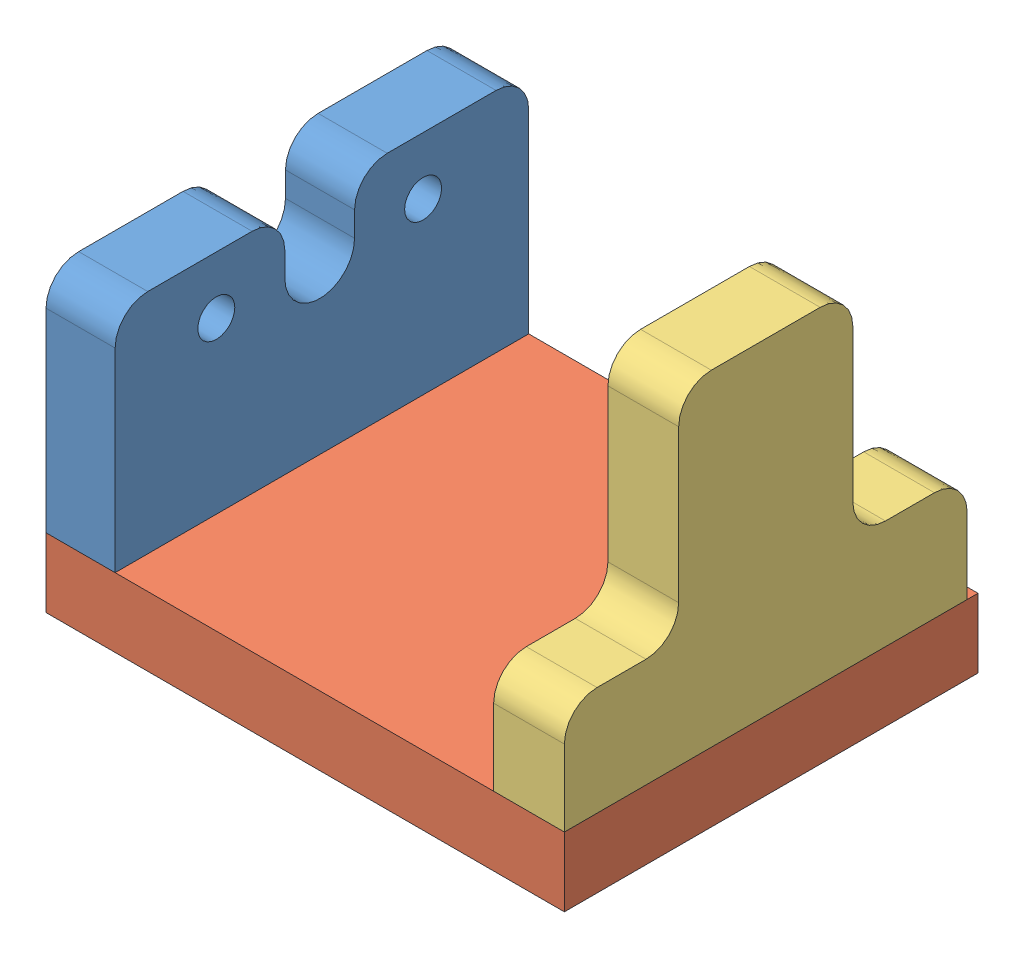
SolidWorks assembly eNSR_test_stand, configuration Default. Lengths in mm.
Overall size (47.63 36.35 38).
4 component instances, 4 part files, 6 mates.
Components (placement in the parent):
- Bracket_Motor-1: Bracket_Motor [Default] at (-176.9192 -50.2023 19.2998) x (0 0 -1) z (-1 0 0) size (38 20.87 6.35)
- bottom-1: bottom [Default] at (-161.6243 -79.421 38.2998) size (47.62 6.35 38)
- motor encoder mount-2: motor encoder mount [Default] at (-13505.3317 14926.929 34568.8017) size (36000 30000 6500)
- sensor_bracket-1: sensor_bracket [Default] at (-120.4993 -73.071 27.7998) x (0 0 -1) z (0 -1 0) size (37 6.5 30)
Mates (geometry in assembly coordinates):
- Coincident2: coincident anti-aligned: plane of Bracket_Motor-1 through (-161.6243 -73.071 0.2998) normal (0 -1 0); plane of bottom-1 through (-161.6243 -73.071 38.2998) normal (0 1 0)
- Coincident3: coincident aligned: plane of Bracket_Motor-1 through (-161.6243 -57.4648 19.5046) normal (-1 0 0); plane of bottom-1 through (-161.6243 -73.071 38.2998) normal (-1 0 0)
- Coincident4: coincident aligned: plane of Bracket_Motor-1 through (-161.6243 -73.071 38.2998) normal (0 0 1); plane of bottom-1 through (-161.6243 -73.071 38.2998) normal (0 0 1)
- Coincident10: coincident: plane of bottom-1 through (-113.9993 -73.071 38.2998) normal (1 0 0); plane of sensor_bracket-1 through (-113.9993 -73.071 27.7998) normal (1 0 0)
- Coincident11: coincident: plane of bottom-1 through (-161.6243 -73.071 38.2998) normal (0 1 0); plane of sensor_bracket-1 through (-113.9993 -73.071 11.7998) normal (0 -1 0)
- Coincident12: coincident aligned: plane of bottom-1 through (-161.6243 -73.071 38.2998) normal (0 0 1); plane of sensor_bracket-1 through (-113.9993 -73.071 38.2998) normal (0 0 1)
